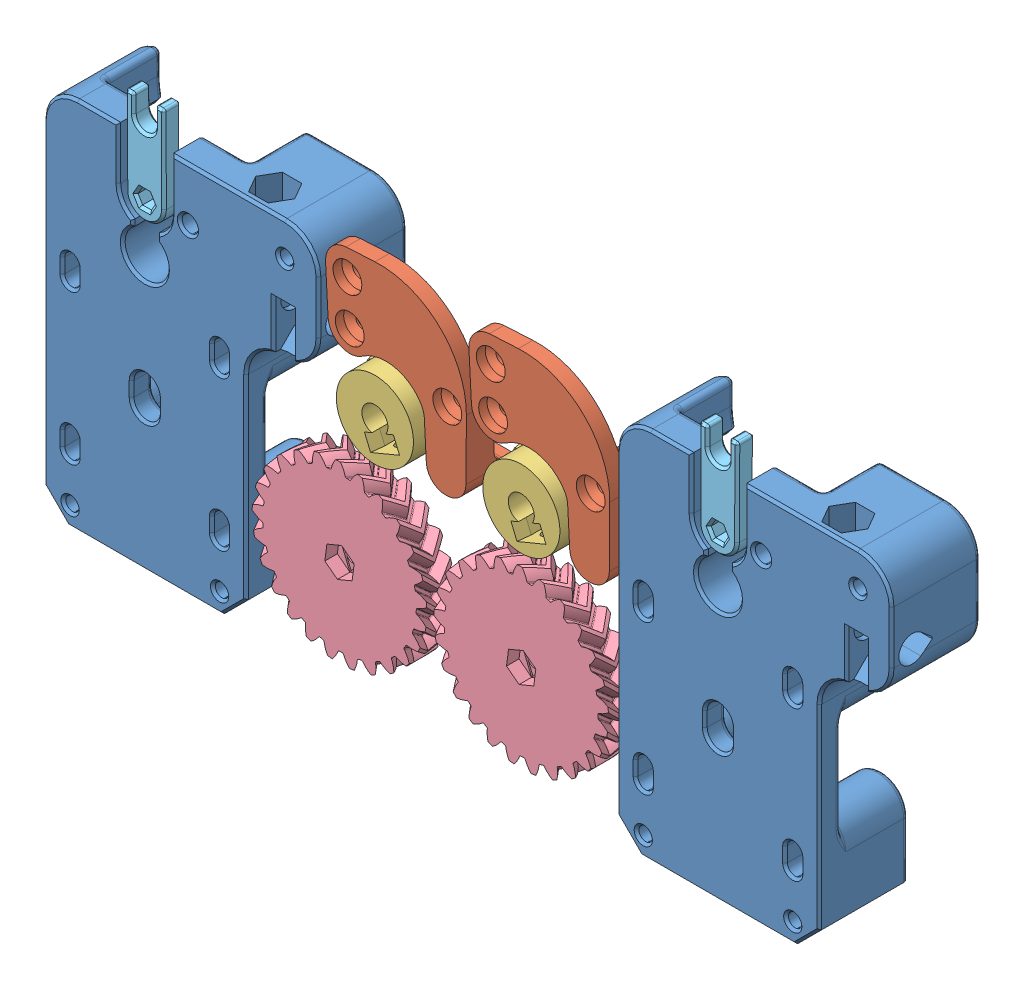
SolidWorks assembly TriColour Tray, configuration Default. Lengths in mm.
Overall size (176.47 86.68 18.81).
10 component instances, 5 part files, 18 mates.
Components (placement in the parent):
- 1306M-1: 1306M [Default] at (17.7338 42.5208 -8.6) size (57.6 77.5 18.81)
- 1309M-1: 1309M [Default] at (89.4718 83.9945 3) x (0.99857 0.053457 0) z (0 0 -1) size (28.5 35.3 9.8)
- 1349-1: 1349 [ISO - RH Helical gear 1M 17T 45HA 20PA 12FW ---17A75H50L0.8N] at (95.8059 61.1548 -9.5) x (0 0 1) z (-0.923728 -0.383049 0) size (13 17.1 17.1)
- 1311-1: 1311 [ISO - RH Helical gear 1M 17T 45HA 20PA 12FW ---17A75H50L0.8N] at (95.7705 32.6161 0) x (0 0 -1) z (0.923728 0.383049 0) size (9 36.33 36.3)
- 1320-1: 1320 [Default] at (136.5956 91.2439 0) x (0.999992 -0.004005 0) z (0 0 -1) size (8 22 3.6)
- 1306M-2: 1306M [Default] at (136.5977 42.6732 -8.6) size (57.6 77.5 18.81)
- 1349-2: 1349 [ISO - RH Helical gear 1M 17T 45HA 20PA 12FW ---17A75H50L0.8N] at (65.4376 61.9593 -9.5) x (0 0 1) z (-0.923728 -0.383049 0) size (13 17.1 17.1)
- 1311-2: 1311 [ISO - RH Helical gear 1M 17T 45HA 20PA 12FW ---17A75H50L0.8N] at (58.0971 32.6552 0) x (0 0 -1) z (0.923728 0.383049 0) size (9 36.33 36.3)
- 1320-2: 1320 [Default] at (17.6455 91.5555 0) x (0.999994 0.003454 0) z (0 0 -1) size (8 22 3.6)
- 1309M-3: 1309M [Default] at (59.74 84.7144 3) x (0.99857 0.053457 0) z (0 0 -1) size (28.5 35.3 9.8)
Mates (geometry in assembly coordinates):
- Coincident1: coincident aligned: plane of 1306M-1 through (17.7338 77.6012 0) normal (0 0 1); plane of assembly through (0 0 0) normal (0 0 1)
- Coincident2: coincident: plane of 1306M-1 through (17.7338 77.6012 0) normal (0 0 1); plane of 1311-1 through (95.7705 32.6161 0) normal (0 0 1)
- Coincident3: coincident: plane of 1306M-1 through (17.7338 77.6012 0) normal (0 0 1); plane of 1349-1 through (95.8059 61.1548 0) normal (0 0 1)
- Coincident4: coincident: plane of 1306M-1 through (17.7338 77.6012 0) normal (0 0 1); plane of 1309M-1 through (89.429 84.7934 0) normal (0 0 1)
- Coincident5: coincident: plane of 1306M-1 through (17.7338 77.6012 0) normal (0 0 1); plane of 1320-1 through (136.5395 77.244 0) normal (0 0 1)
- Coincident6: coincident: plane of 1306M-1 through (17.7338 77.6012 0) normal (0 0 1); plane of 1311-2 through (58.0971 32.6552 0) normal (0 0 1)
- Coincident7: coincident: plane of 1306M-1 through (17.7338 77.6012 0) normal (0 0 1); plane of 1349-2 through (65.4376 61.9593 0) normal (0 0 1)
- Coincident10: coincident: plane of 1306M-1 through (17.7338 77.6012 0) normal (0 0 1); plane of 1320-2 through (17.6938 77.5556 0) normal (0 0 1)
- Coincident11: coincident: plane of 1306M-1 through (17.7338 77.6012 0) normal (0 0 1); plane of 1306M-2 through (136.5977 77.7535 0) normal (0 0 1)
- Coincident13: coincident aligned: plane of 1306M-1 through (17.7338 77.6012 0) normal (0 0 1); plane of 1309M-3 through (59.6973 85.5133 0) normal (0 0 1)
- Coincident14: coincident aligned: plane of 1306M-1 through (17.7338 77.6012 0) normal (0 0 1); plane of 1320-2 through (17.6938 77.5556 0) normal (0 0 1)
- Coincident15: coincident aligned: plane of 1306M-1 through (17.7338 77.6012 0) normal (0 0 1); plane of 1309M-1 through (89.429 84.7934 0) normal (0 0 1)
- Coincident16: coincident aligned: plane of 1306M-1 through (17.7338 77.6012 0) normal (0 0 1); plane of 1320-1 through (136.5395 77.244 0) normal (0 0 1)
- Coincident17: coincident aligned: plane of 1306M-1 through (17.7338 77.6012 0) normal (0 0 1); plane of 1306M-2 through (136.5977 77.7535 0) normal (0 0 1)
- Coincident18: coincident aligned: plane of 1306M-1 through (17.7338 77.6012 0) normal (0 0 1); plane of 1349-1 through (95.8059 61.1548 0) normal (0 0 1)
- Coincident19: coincident aligned: plane of 1306M-1 through (17.7338 77.6012 0) normal (0 0 1); plane of 1349-2 through (65.4376 61.9593 0) normal (0 0 1)
- Coincident20: coincident aligned: plane of 1306M-1 through (17.7338 77.6012 0) normal (0 0 1); plane of 1311-1 through (95.7705 32.6161 0) normal (0 0 1)
- Coincident21: coincident aligned: plane of 1306M-1 through (17.7338 77.6012 0) normal (0 0 1); plane of 1311-2 through (58.0971 32.6552 0) normal (0 0 1)
